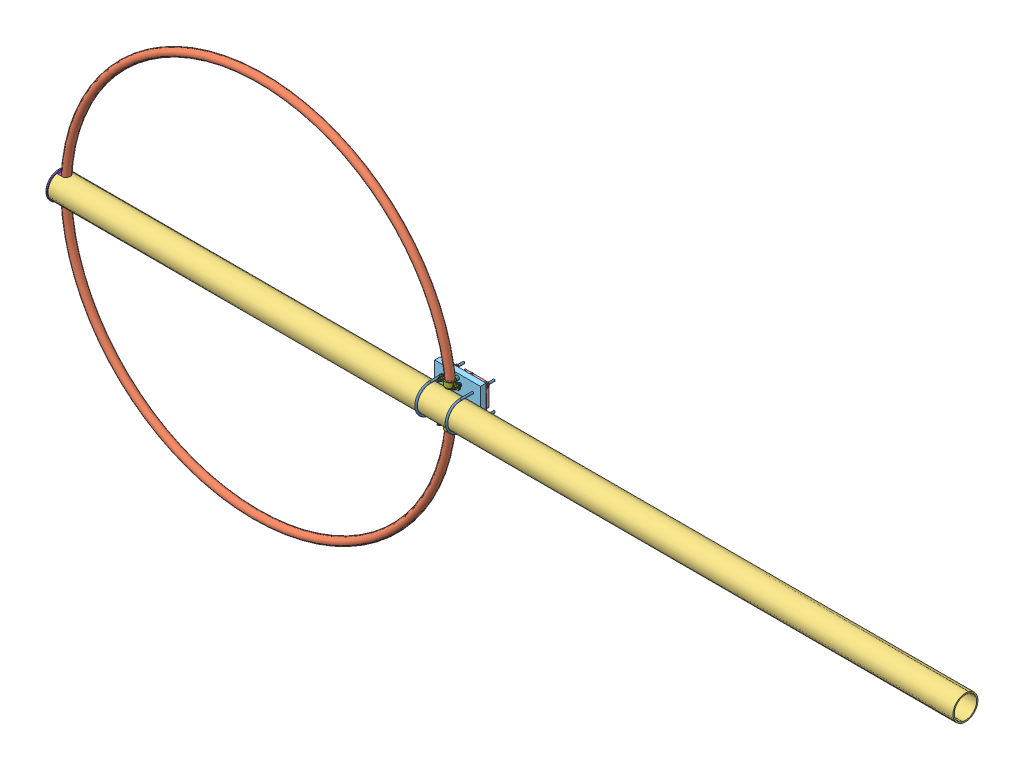
SolidWorks assembly antenna_assembly, configuration Default. Lengths in mm.
Overall size (2385 1020 139.26).
28 component instances, 13 part files, 70 mates.
Components (placement in the parent):
- u_bolt-1: u_bolt [Default] at (-8.3748 79.0822 109.564) size (5 77 128.5)
- alu_loop-1: alu_loop [Default] at (-544.7182 78.8322 103.0491) x (0 1 0) z (0.01303 0 0.999915) size (1020 1016.99 21.15)
- fiberglass_rod-1: fiberglass_rod [Default] at (-1059.6757 111.5822 109.564) x (0 -1 0) z (-1 0 0) size (66 66 2380)
- preamp-1: preamp [Default] at (-48.3748 79.0822 51.564) x (0 1 0) z (0 0 1) size (84 102 35)
- u_bolt-2: u_bolt [Default] at (-88.3748 79.0822 109.564) size (5 77 128.5)
- mounting_bracket-1: mounting_bracket [Default] at (-48.3748 79.0822 76.564) x (0 1 0) z (0 0 1) size (120 120 15)
- standoff_clamp-1: standoff_clamp [Default] at (-48.3748 135.3322 76.564) x (1 0 0) z (0 -1 0) size (49.9 19.02 12.5)
- standoff_clamp_top-1: standoff_clamp_top [Default] at (-48.3748 122.8322 116.5986) x (1 0 0) z (0 1 0) size (49.9 11 12.5)
- standoff_clamp-2: standoff_clamp [Default] at (-48.3748 22.8322 76.564) x (-1 0 0) z (0 1 0) size (49.9 19.02 12.5)
- standoff_clamp_top-2: standoff_clamp_top [Default] at (-48.3748 35.3322 116.5986) x (-1 0 0) z (0 -1 0) size (49.9 11 12.5)
- lid-1: lid [Default] at (-1064.6757 78.5822 109.564) x (0 -0.772797 0.634653) z (0 0.634653 0.772797) size (70 15 70)
- hex nut gradec_din-2: hex nut gradec_din [Hexagon Nut ISO 4034 - M5 - N] at (-29.6749 29.0822 99.5813) x (-0.923728 -0.383049 0) z (0 0 -1) size (8 9.24 5.6)
- hex nut gradec_din-3: hex nut gradec_din [Hexagon Nut ISO 4034 - M5 - N] at (-67.0747 29.0822 105.1813) size (8 9.24 5.6)
- hex nut gradec_din-4: hex nut gradec_din [Hexagon Nut ISO 4034 - M5 - N] at (-29.6749 129.0822 105.1813) size (8 9.24 5.6)
- hex nut gradec_din-5: hex nut gradec_din [Hexagon Nut ISO 4034 - M5 - N] at (-67.0747 129.0822 105.1813) x (0.99308 -0.11744 0) z (0 0 1) size (8 9.24 5.6)
- hex flange bolt_din-1: hex flange bolt_din [DIN 6921 - M5 x 16 x 16-N] at (-67.0747 129.0822 88.1813) x (0 0 1) z (-0.766978 0.641673 0) size (21.4 11.8 11.8)
- hex flange bolt_din-2: hex flange bolt_din [DIN 6921 - M5 x 16 x 16-N] at (-67.0747 29.0822 88.1813) x (0 0 1) z (-0.743081 -0.669201 0) size (21.4 11.8 11.8)
- hex flange bolt_din-3: hex flange bolt_din [DIN 6921 - M5 x 16 x 16-N] at (-29.6749 29.0822 88.1813) x (0 0 1) z (-0.997414 -0.071871 0) size (21.4 11.8 11.8)
- hex flange bolt_din-4: hex flange bolt_din [DIN 6921 - M5 x 16 x 16-N] at (-29.6749 129.0822 88.1813) x (0 0 1) z (-0.997716 0.067547 0) size (21.4 11.8 11.8)
- hex flange bolt_din-5: hex flange bolt_din [DIN 6921 - M6 x 20 x 20-N] at (-48.3748 129.0822 54.964) x (0 0 1) z (-0.754004 -0.65687 0) size (26.6 14.2 14.2)
- hex flange bolt_din-6: hex flange bolt_din [DIN 6921 - M6 x 20 x 20-N] at (-48.3748 29.0822 54.964) x (0 0 1) z (-0.357135 -0.934053 0) size (26.6 14.2 14.2)
- spacer-1: spacer [Default] at (-13.3748 48.0822 41.564) size (10 10 20)
- spacer-2: spacer [Default] at (-3.3748 120.0822 41.564) x (0 -1 0) z (0 0 1) size (10 10 20)
- bridge_spacer-1: bridge_spacer [Default] at (-83.3748 79.0822 48.064) x (0 1 0) z (-1 0 0) size (82 20 10)
- hex flange nut gradea_iso-1: hex flange nut gradea_iso [ISO - 4161 - M5 - N] at (-8.3748 43.0822 36.564) x (0.923728 0.383049 0) z (0 0 -1) size (11.8 11.8 5)
- hex flange nut gradea_iso-2: hex flange nut gradea_iso [ISO - 4161 - M5 - N] at (-88.3748 115.0822 36.564) x (0.923728 0.383049 0) z (0 0 -1) size (11.8 11.8 5)
- hex flange nut gradea_iso-3: hex flange nut gradea_iso [ISO - 4161 - M5 - N] at (-88.3748 43.0822 36.564) x (0.923728 0.383049 0) z (0 0 -1) size (11.8 11.8 5)
- hex flange nut gradea_iso-4: hex flange nut gradea_iso [ISO - 4161 - M5 - N] at (-8.3748 115.0822 36.564) x (0.923728 0.383049 0) z (0 0 -1) size (11.8 11.8 5)
Mates (geometry in assembly coordinates):
- Concentric10: concentric anti-aligned: cylinder of u_bolt-2 through (-88.3748 43.0822 19.564) axis (0 0 1) radius 2.5; cylinder of mounting_bracket-1 through (-88.3748 43.0822 76.565) axis (0 0 -1) radius 2.5
- Concentric11: concentric anti-aligned: cylinder of u_bolt-2 through (-88.3748 115.0822 19.564) axis (0 0 1) radius 2.5; cylinder of mounting_bracket-1 through (-88.3748 115.0822 76.565) axis (0 0 -1) radius 2.5
- Distance1: distance = 42 mm: plane of u_bolt-2 through (-88.3748 43.0822 19.564) normal (0 0 -1); plane of mounting_bracket-1 through (-48.3748 79.0822 61.564) normal (0 0 -1)
- Concentric12: concentric anti-aligned: cylinder of u_bolt-1 through (-8.3748 43.0822 19.564) axis (0 0 1) radius 2.5; cylinder of mounting_bracket-1 through (-8.3748 43.0822 76.565) axis (0 0 -1) radius 2.5
- Concentric14: concentric anti-aligned: cylinder of u_bolt-1 through (-8.3748 115.0822 19.564) axis (0 0 1) radius 2.5; cylinder of mounting_bracket-1 through (-8.3748 115.0822 76.565) axis (0 0 -1) radius 2.5
- Distance2: distance = 42 mm: plane of u_bolt-1 through (-8.3748 115.0822 19.564) normal (0 0 -1); plane of mounting_bracket-1 through (-48.3748 79.0822 61.564) normal (0 0 -1)
- Coincident9: coincident: plane of preamp-1 through (-48.3748 79.0822 61.564) normal (0 0 1); plane of mounting_bracket-1 through (-48.3748 79.0822 61.564) normal (0 0 -1)
- Concentric17: concentric aligned: cylinder of mounting_bracket-1 through (-48.3748 29.0822 76.565) axis (0 0 -1) radius 3; cylinder of standoff_clamp-2 through (-48.3748 29.0822 85.674) axis (0 0 -1) radius 3
- Coincident11: coincident: plane of mounting_bracket-1 through (-48.3748 79.0822 76.564) normal (0 0 1); plane of standoff_clamp-2 through (-53.3748 35.3322 76.564) normal (0 0 -1)
- Parallel2: parallel aligned: plane of mounting_bracket-1 through (-108.3748 19.0822 61.564) normal (0 -1 0); plane of standoff_clamp-2 through (-60.7441 22.8322 92.5813) normal (0 -1 0)
- Coincident13: coincident: plane of mounting_bracket-1 through (-48.3748 79.0822 76.564) normal (0 0 1); plane of standoff_clamp-1 through (-43.3748 122.8322 76.564) normal (0 0 -1)
- Concentric18: concentric aligned: cylinder of mounting_bracket-1 through (-48.3748 129.0822 76.565) axis (0 0 -1) radius 3; cylinder of standoff_clamp-1 through (-48.3748 129.0822 85.674) axis (0 0 -1) radius 3
- Parallel3: parallel aligned: plane of mounting_bracket-1 through (-108.3748 139.0822 61.564) normal (0 1 0); plane of standoff_clamp-1 through (-36.0055 135.3322 92.5813) normal (0 1 0)
- Tangent1: tangent: cylinder of fiberglass_rod-1 through (1320.3243 78.5822 109.564) axis (-1 0 0) radius 33; plane of mounting_bracket-1 through (-48.3748 79.0822 76.564) normal (0 0 1)
- Parallel4: parallel aligned: plane of fiberglass_rod-1 through (1320.3243 78.5822 109.564) normal (1 0 0); plane of mounting_bracket-1 through (11.6252 19.0822 61.564) normal (1 0 0)
- Tangent3: tangent: cylinder of fiberglass_rod-1 through (1320.3243 78.5822 109.564) axis (-1 0 0) radius 33; cylinder of u_bolt-2 through (-88.3748 43.0822 19.564) axis (0 0 1) radius 2.5
- Concentric21: concentric: cylinder of alu_loop-1 through (-48.3748 118.8322 96.5813) axis (0 1 0) radius 10; cylinder of standoff_clamp-1 through (-48.3748 122.8322 96.5813) axis (0 1 0) radius 10
- Distance3: distance = 4 mm: plane of standoff_clamp-1 through (-36.0055 122.8322 92.5813) normal (0 -1 0); plane of alu_loop-1 through (-48.3748 118.8322 96.5813) normal (0 -1 0)
- Parallel7: parallel: plane of fiberglass_rod-1 through (-1059.6757 45.5822 99.564) normal (0 0 1); plane of mounting_bracket-1 through (-48.3748 79.0822 76.564) normal (0 0 1)
- Tangent8: tangent: torus of alu_loop-1; plane of fiberglass_rod-1 through (-1059.6757 45.5822 119.564) normal (0 0 -1)
- Tangent10: tangent: torus of alu_loop-1; cylinder of fiberglass_rod-1 through (-1044.6757 45.5822 109.564) axis (0 1 0) radius 10
- Concentric22: concentric: cylinder of alu_loop-1 through (-48.3748 118.8322 96.5813) axis (0 1 0) radius 10; cylinder of standoff_clamp_top-1 through (-48.3748 135.3322 96.5813) axis (0 -1 0) radius 10
- Coincident18: coincident aligned: plane of standoff_clamp-1 through (-36.0055 135.3322 92.5813) normal (0 1 0); plane of standoff_clamp_top-1 through (-36.0055 135.3322 100.5813) normal (0 1 0)
- Concentric23: concentric: cylinder of alu_loop-1 through (-48.3748 38.8322 96.5813) axis (0 -1 0) radius 10; cylinder of standoff_clamp_top-2 through (-48.3748 22.8322 96.5813) axis (0 1 0) radius 10
- Parallel8: parallel aligned: plane of standoff_clamp-2 through (-60.7441 22.8322 92.5813) normal (0 -1 0); plane of standoff_clamp_top-2 through (-60.7441 22.8322 100.5813) normal (0 -1 0)
- Coincident23: coincident aligned: plane of standoff_clamp-2 through (-60.7441 22.8322 92.5813) normal (0 -1 0); plane of standoff_clamp_top-2 through (-60.7441 22.8322 100.5813) normal (0 -1 0)
- Concentric24: concentric: cylinder of fiberglass_rod-1 through (1320.3243 78.5822 109.564) axis (-1 0 0) radius 29.5; cylinder of lid-1 through (-1064.6757 78.5822 109.564) axis (1 0 0) radius 29.5
- Coincident24: coincident anti-aligned: plane of fiberglass_rod-1 through (-1059.6757 78.5822 109.564) normal (-1 0 0); plane of lid-1 through (-1059.6757 55.7847 128.2863) normal (1 0 0)
- Coincident34: coincident aligned: plane of standoff_clamp-2 through (-73.3247 35.3322 95.5813) normal (-1 0 0); plane of standoff_clamp_top-2 through (-73.3247 22.8322 97.5813) normal (-1 0 0)
- Coincident35: coincident aligned: plane of standoff_clamp-1 through (-73.3247 122.8322 95.5813) normal (-1 0 0); plane of standoff_clamp_top-1 through (-73.3247 135.3322 97.5813) normal (-1 0 0)
- Coincident37: coincident: plane of standoff_clamp_top-2 through (-68.3247 22.8322 99.5813) normal (0 0 1); plane of hex nut gradec_din-3 through (-67.0747 33.701 99.5813) normal (0 0 -1)
- Concentric34: concentric anti-aligned: cylinder of standoff_clamp_top-2 through (-67.0747 29.0822 108.5823) axis (0 0 -1) radius 2.5; cylinder of hex nut gradec_din-3 through (-67.0747 29.0822 99.5813) axis (0 0 1) radius 2.1
- Coincident38: coincident: plane of standoff_clamp_top-2 through (-28.4249 22.8322 99.5813) normal (0 0 1); plane of hex nut gradec_din-2 through (-31.4442 33.3488 99.5813) normal (0 0 -1)
- Concentric35: concentric aligned: cylinder of standoff_clamp_top-2 through (-29.6749 29.0822 108.5823) axis (0 0 -1) radius 2.5; cylinder of hex nut gradec_din-2 through (-29.6749 29.0822 105.1813) axis (0 0 -1) radius 2.1
- Concentric36: concentric anti-aligned: cylinder of standoff_clamp_top-1 through (-67.0747 129.0822 108.5823) axis (0 0 -1) radius 2.5; cylinder of hex nut gradec_din-5 through (-67.0747 129.0822 99.5813) axis (0 0 1) radius 2.1
- Coincident39: coincident: plane of standoff_clamp_top-1 through (-68.3247 135.3322 99.5813) normal (0 0 1); plane of hex nut gradec_din-5 through (-66.5323 133.6691 99.5813) normal (0 0 -1)
- Coincident40: coincident: plane of standoff_clamp_top-1 through (-28.4249 135.3322 99.5813) normal (0 0 1); plane of hex nut gradec_din-4 through (-29.6749 133.701 99.5813) normal (0 0 -1)
- Concentric38: concentric anti-aligned: cylinder of standoff_clamp_top-1 through (-29.6749 129.0822 108.5823) axis (0 0 -1) radius 2.5; cylinder of hex nut gradec_din-4 through (-29.6749 129.0822 99.5813) axis (0 0 1) radius 2.1
- Concentric39: concentric anti-aligned: cylinder of standoff_clamp-1 through (-67.0747 129.0822 76.563) axis (0 0 1) radius 2.5; cylinder of hex flange bolt_din-1 through (-67.0747 129.0822 88.1813) axis (0 0 -1) radius 2.5
- Coincident41: coincident: plane of standoff_clamp-1 through (-68.3247 122.8322 93.5813) normal (0 0 -1); plane of hex flange bolt_din-1 through (-64.1109 132.6248 93.5813) normal (0 0 1)
- Concentric40: concentric anti-aligned: cylinder of standoff_clamp-1 through (-29.6749 129.0822 76.563) axis (0 0 1) radius 2.5; cylinder of hex flange bolt_din-4 through (-29.6749 129.0822 88.1813) axis (0 0 -1) radius 2.5
- Coincident42: coincident: plane of standoff_clamp-1 through (-23.4249 122.8322 93.5813) normal (0 0 -1); plane of hex flange bolt_din-4 through (-29.363 133.6905 93.5813) normal (0 0 1)
- Concentric41: concentric anti-aligned: cylinder of standoff_clamp-2 through (-29.6749 29.0822 76.563) axis (0 0 1) radius 2.5; cylinder of hex flange bolt_din-3 through (-29.6749 29.0822 88.1813) axis (0 0 -1) radius 2.5
- Coincident43: coincident: plane of standoff_clamp-2 through (-28.4249 35.3322 93.5813) normal (0 0 -1); plane of hex flange bolt_din-3 through (-30.0069 33.6891 93.5813) normal (0 0 1)
- Concentric42: concentric anti-aligned: cylinder of standoff_clamp-2 through (-67.0747 29.0822 76.563) axis (0 0 1) radius 2.5; cylinder of hex flange bolt_din-2 through (-67.0747 29.0822 88.1813) axis (0 0 -1) radius 2.5
- Coincident44: coincident: plane of standoff_clamp-2 through (-73.3247 35.3322 93.5813) normal (0 0 -1); plane of hex flange bolt_din-2 through (-70.1656 32.5144 93.5813) normal (0 0 1)
- Concentric43: concentric aligned: cylinder of mounting_bracket-1 through (-48.3748 29.0822 76.565) axis (0 0 -1) radius 3; cylinder of hex flange bolt_din-6 through (-48.3748 29.0822 54.964) axis (0 0 -1) radius 3
- Coincident45: coincident: plane of mounting_bracket-1 through (-48.3748 79.0822 61.564) normal (0 0 -1); plane of hex flange bolt_din-6 through (-53.7676 31.1442 61.564) normal (0 0 1)
- Concentric44: concentric aligned: cylinder of mounting_bracket-1 through (-48.3748 129.0822 76.565) axis (0 0 -1) radius 3; cylinder of hex flange bolt_din-5 through (-48.3748 129.0822 54.964) axis (0 0 -1) radius 3
- Coincident46: coincident: plane of mounting_bracket-1 through (-48.3748 79.0822 61.564) normal (0 0 -1); plane of hex flange bolt_din-5 through (-52.1673 133.4355 61.564) normal (0 0 1)
- Coincident48: coincident: plane of preamp-1 through (-48.3748 79.0822 61.564) normal (0 0 1); plane of mounting_bracket-1 through (-48.3748 79.0822 61.564) normal (0 0 -1)
- Distance5: distance = 9 mm: line of preamp-1 through (-99.3748 104.0822 61.564) axis (0 -1 0); line of mounting_bracket-1 through (-108.3748 139.0822 61.564) axis (0 -1 0)
- Distance6: distance = 30 mm: line of preamp-1 through (-94.3748 49.0822 61.564) axis (1 0 0); line of mounting_bracket-1 through (-108.3748 19.0822 61.564) axis (1 0 0)
- Concentric45: concentric: cylinder of u_bolt-1 through (-8.3748 43.0822 19.564) axis (0 0 1) radius 2.5; cylinder of spacer-1 through (-8.3748 43.0822 61.564) axis (0 0 -1) radius 2.5
- Coincident49: coincident: plane of mounting_bracket-1 through (-48.3748 79.0822 61.564) normal (0 0 -1); plane of spacer-1 through (-13.3748 48.0822 61.564) normal (0 0 1)
- Parallel9: parallel: plane of mounting_bracket-1 through (11.6252 19.0822 61.564) normal (1 0 0); plane of spacer-1 through (-3.3748 48.0822 61.564) normal (1 0 0)
- Concentric46: concentric: cylinder of u_bolt-1 through (-8.3748 115.0822 19.564) axis (0 0 1) radius 2.5; cylinder of spacer-2 through (-8.3748 115.0822 61.564) axis (0 0 -1) radius 2.5
- Coincident51: coincident: plane of mounting_bracket-1 through (-48.3748 79.0822 61.564) normal (0 0 -1); plane of spacer-2 through (-3.3748 120.0822 61.564) normal (0 0 1)
- Parallel10: parallel: plane of mounting_bracket-1 through (11.6252 19.0822 61.564) normal (1 0 0); plane of spacer-2 through (-3.3748 120.0822 61.564) normal (1 0 0)
- Concentric50: concentric: cylinder of u_bolt-2 through (-88.3748 43.0822 19.564) axis (0 0 1) radius 2.5; cylinder of bridge_spacer-1 through (-88.3748 43.0822 61.565) axis (0 0 -1) radius 2.5
- Concentric51: concentric: cylinder of u_bolt-2 through (-88.3748 115.0822 19.564) axis (0 0 1) radius 2.5; cylinder of bridge_spacer-1 through (-88.3748 115.0822 61.565) axis (0 0 -1) radius 2.5
- Coincident53: coincident: plane of mounting_bracket-1 through (-48.3748 79.0822 61.564) normal (0 0 -1); plane of bridge_spacer-1 through (-93.3748 79.0822 61.564) normal (0 0 1)
- Concentric52: concentric anti-aligned: cylinder of u_bolt-2 through (-88.3748 43.0822 19.564) axis (0 0 1) radius 2.5; cylinder of hex flange nut gradea_iso-3 through (-88.3748 43.0822 41.564) axis (0 0 -1) radius 2.1
- Coincident54: coincident: plane of bridge_spacer-1 through (-93.3748 79.0822 41.564) normal (0 0 -1); plane of hex flange nut gradea_iso-3 through (-86.6056 38.8157 41.564) normal (0 0 1)
- Concentric53: concentric anti-aligned: cylinder of u_bolt-2 through (-88.3748 115.0822 19.564) axis (0 0 1) radius 2.5; cylinder of hex flange nut gradea_iso-2 through (-88.3748 115.0822 41.564) axis (0 0 -1) radius 2.1
- Coincident55: coincident anti-aligned: plane of bridge_spacer-1 through (-93.3748 79.0822 41.564) normal (0 0 -1); plane of hex flange nut gradea_iso-2 through (-86.6056 110.8157 41.564) normal (0 0 1)
- Concentric54: concentric anti-aligned: cylinder of u_bolt-1 through (-8.3748 43.0822 19.564) axis (0 0 1) radius 2.5; cylinder of hex flange nut gradea_iso-1 through (-8.3748 43.0822 41.564) axis (0 0 -1) radius 2.1
- Coincident56: coincident anti-aligned: plane of spacer-1 through (-13.3748 48.0822 41.564) normal (0 0 -1); plane of hex flange nut gradea_iso-1 through (-6.6056 38.8157 41.564) normal (0 0 1)
- Concentric55: concentric anti-aligned: cylinder of u_bolt-1 through (-8.3748 115.0822 19.564) axis (0 0 1) radius 2.5; cylinder of hex flange nut gradea_iso-4 through (-8.3748 115.0822 41.564) axis (0 0 -1) radius 2.1
- Coincident57: coincident anti-aligned: plane of spacer-2 through (-3.3748 120.0822 41.564) normal (0 0 -1); plane of hex flange nut gradea_iso-4 through (-6.6056 110.8157 41.564) normal (0 0 1)
